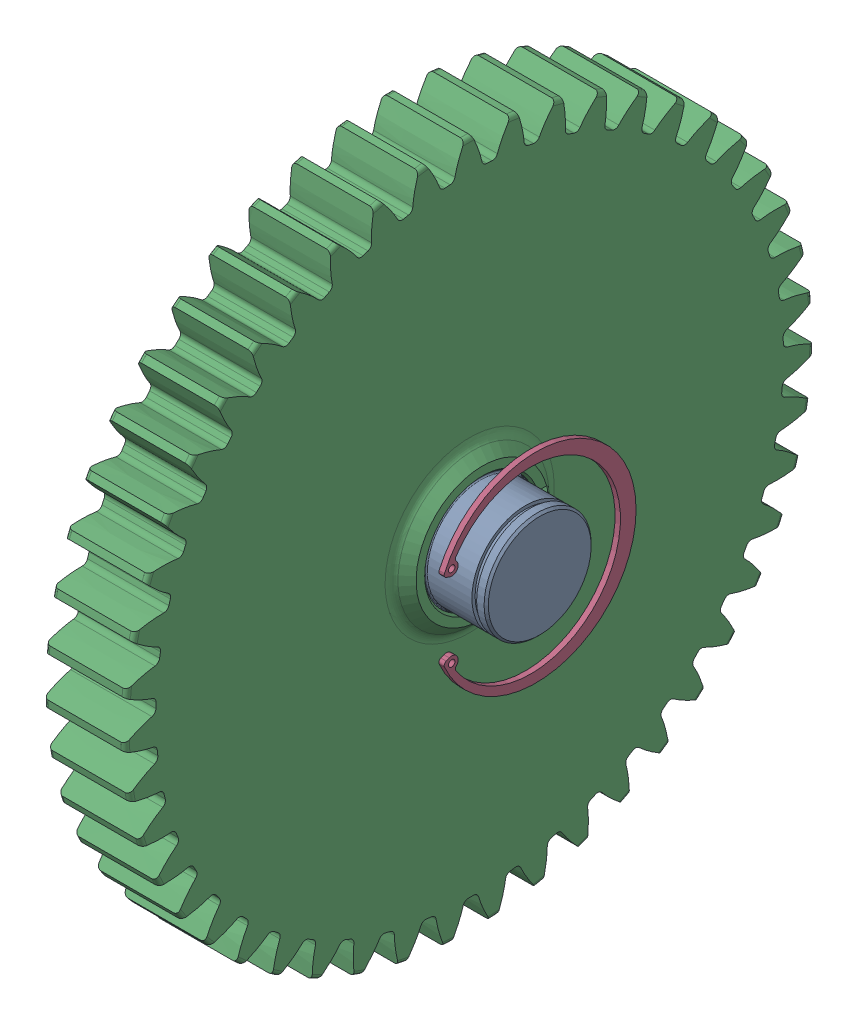
SolidWorks assembly g1_3_1_1_3_2, configuration 默认. Lengths in mm.
Overall size (103.5 321.87 322.01).
5 component instances, 4 part files, 0 mates.
Components (placement in the parent):
- g1_3_1_1_3-1_2-1: g1_3_1_1_3-1_2 [默认] at origin size (103.5 52 52)
- 16x10x45_gb1096_2-1: 16x10x45_gb1096_2 [默认] at (-0.5 0 25) x (1 0 0) z (0 0 -1) size (45 16 10)
- _X2_60F08F6E_X0_g1_3_1_1_3-2_2-1: _X2_60F08F6E_X0_g1_3_1_1_3-2_2 [默认] at (25 0 0) x (0 0 1) z (1 0 0) size (322.01 321.87 50.08)
- 90_gb893_1_2-1: 90_gb893_1_2 [默认] at (45.05 0 -2.4333) x (0 1 0) z (1 0 0) size (93.5 89.63 2.5)
- 90_gb893_1_2-2: 90_gb893_1_2 [默认] at (-47.55 0 -2.4333) x (0 1 0) z (1 0 0) size (93.5 89.63 2.5)
